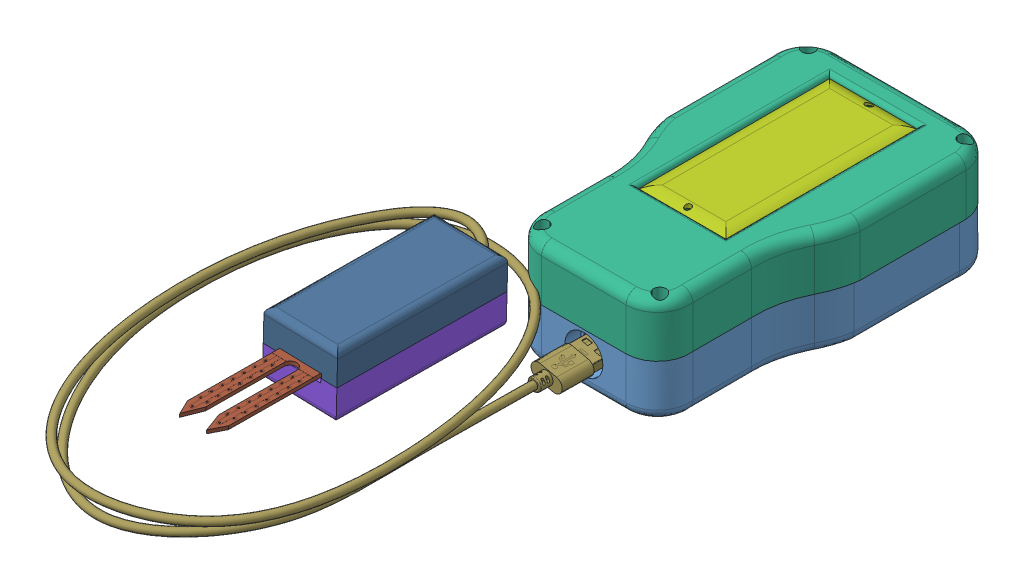
SolidWorks assembly Assem2, configuration Default. Lengths in mm.
Overall size (141.14 65.79 345.88).
13 component instances, 13 part files, 23 mates.
Components (placement in the parent):
- top-1: top [Default] at (67.1449 58.7615 115.5242) size (90.51 25.28 150)
- LCD-1: LCD [Default] at (67.061 64.7615 73.0708) x (-1 0 -0.000027) z (-0.000027 0 1) size (80.07 12.25 36.01)
- 1x4-keypad.stp-1: 1x4-keypad.stp [Default] at (67.0223 58.7615 110.1642) x (-1 0 0) z (0 0 1) size (69 7.1 20)
- WP1513GT.stp-1: WP1513GT.stp [Default] at (82.9683 65.6804 146.2483) x (0.92428 0 0.381715) z (0 -1 0) size (5.45 5.9 35.6)
- WP1513IT.stp-1: WP1513IT.stp [Default] at (51.3214 65.5043 146.2483) x (-0.785055 0 0.619426) z (0 -1 0) size (5.45 5.9 35.6)
- bottum-1: bottum [Default] at (67.1449 108.7615 115.5242) x (-1 0 0) z (0 0 1) size (90.51 25.68 150)
- BatteryLid-1: BatteryLid [Default] at (66.5924 106.7615 97.0343) x (1 0 0) z (0 1 0) size (42 91 2)
- sensortop-1: sensortop [Default] at (40.5905 82.4081 239.8119) x (-0.00509 0.003088 0.999982) z (-0.999709 0.023576 -0.005161) size (85 15 35)
- DHT11-1: DHT11 [Default] at (23.5549 91.3797 242.5446) x (0.999709 -0.023576 0.005161) z (-0.023591 -0.999717 0.002967) size (14 35.05 6.5)
- sensorbottum-1: sensorbottum [Default] at (17.8788 112.9519 239.602) x (-0.00509 0.003088 0.999982) z (0.999709 -0.023576 0.005161) size (85 15 35)
- Soil-Moisture-Sensor-Probe.stp-1: Soil-Moisture-Sensor-Probe.stp [Default] at (29.0609 98.1403 275.4531) x (0.999709 -0.023576 0.005161) z (0.00509 -0.003088 -0.999982) size (19.5 7 64.88)
- Тело9-1: Тело9 [По умолчанию] at (26.7121 97.0127 313.1556) x (0.004423 -0.007372 -0.999963) z (0.976916 -0.213544 0.005896) size (205.75 32.05 104.13)
- RockerSwitch-1: RockerSwitch [Default] at (32.3085 94.0875 80.8333) x (0 0 1) z (-1 0 0) size (21 14.8 24.8)
Mates (geometry in assembly coordinates):
- Parallel3: parallel anti-aligned: plane of top-1 through (96.4561 61.7615 87.4448) normal (0 1 0); plane of LCD-1 through (67.061 64.7615 73.0708) normal (0 -1 0)
- Coincident9: coincident anti-aligned: plane of top-1 through (62.7688 58.7615 97.6198) normal (0 -1 0); plane of 1x4-keypad.stp-1 through (67.0223 58.7615 110.1642) normal (0 1 0)
- Parallel6: parallel anti-aligned: line of top-1 through (28.1449 58.7615 88.9162) axis (1 0 0); line of 1x4-keypad.stp-1 through (101.5223 58.2615 120.1642) axis (-1 0 0)
- Concentric1: concentric aligned: cylinder of top-1 through (82.9683 68.7615 146.2483) axis (0 -1 0) radius 2.5; cone of WP1513GT.stp-1 through (82.9683 62.0304 146.2483) axis (0 -1 0)
- Concentric2: concentric aligned: cylinder of top-1 through (51.3214 68.7615 146.2483) axis (0 -1 0) radius 2.5; cone of WP1513IT.stp-1 through (51.3214 61.8543 146.2483) axis (0 -1 0)
- Parallel9: parallel anti-aligned: line of top-1 through (24.4204 83.7615 53.386) axis (-0.000027 0 1); line of LCD-1 through (27.0606 66.3615 88.5697) axis (0.000027 0 -1)
- Coincident18: coincident anti-aligned: plane of top-1 through (96.4561 61.7615 87.4448) normal (0 1 0); plane of LCD-1 through (67.061 61.7615 73.0708) normal (0 -1 0)
- Coincident21: coincident anti-aligned: line of top-1 through (37.1453 83.7615 39.2483) axis (1 0 0); line of bottum-1 through (97.1444 83.7615 39.2483) axis (-1 0 0)
- Coincident22: coincident anti-aligned: line of top-1 through (47.1449 83.7615 189.2483) axis (1 0 0); line of bottum-1 through (87.1449 83.7615 189.2483) axis (-1 0 0)
- Coincident25: coincident: cylinder of bottum-1 through (43.5924 106.7615 142.5343) axis (0 0 -1) radius 2; line of BatteryLid-1 through (45.5924 106.7615 51.5343) axis (0 0 1)
- Coincident26: coincident aligned: plane of bottum-1 through (71.5209 108.7615 97.6198) normal (0 1 0); plane of BatteryLid-1 through (66.5924 108.7615 97.0343) normal (0 1 0)
- Coincident27: coincident aligned: line of bottum-1 through (72.4595 106.7615 142.5343) axis (1 0 0); line of BatteryLid-1 through (45.5924 106.7615 142.5343) axis (1 0 0)
- Distance5: distance = 5.5591 mm anti-aligned: plane of sensortop-1 through (40.6612 85.4072 239.803) normal (0.023591 0.999717 -0.002967); plane of DHT11-1 through (23.5549 91.3797 242.5446) normal (-0.023591 -0.999717 0.002967)
- Parallel13: parallel aligned: line of sensortop-1 through (13.586 85.9699 214.1275) axis (-0.00509 0.003088 0.999982); line of DHT11-1 through (22.6478 92.3611 228.9867) axis (-0.00509 0.003088 0.999982)
- Coincident31: coincident anti-aligned: plane of sensorbottum-1 through (39.238 99.5499 275.2172) normal (-0.023591 -0.999717 0.002967); plane of Soil-Moisture-Sensor-Probe.stp-1 through (29.0666 99.81 281.9724) normal (0.023591 0.999717 -0.002967)
- Concentric3: concentric aligned: circle of sensorbottum-1; circle of Soil-Moisture-Sensor-Probe.stp-1
- Concentric4: concentric aligned: circle of sensorbottum-1; circle of Soil-Moisture-Sensor-Probe.stp-1
- Concentric5: concentric anti-aligned: circle of sensortop-1; circle of DHT11-1
- Coincident32: coincident anti-aligned: line of sensortop-1 through (25.4461 97.6668 205.1516) axis (-0.999709 0.023576 -0.005161); line of sensorbottum-1 through (11.9155 97.9859 205.0817) axis (0.999709 -0.023576 0.005161)
- Coincident33: coincident anti-aligned: line of sensortop-1 through (11.9155 97.9859 205.0817) axis (-0.00509 0.003088 0.999982); line of sensorbottum-1 through (11.5083 98.233 285.0803) axis (0.00509 -0.003088 -0.999982)
- Coincident34: coincident anti-aligned: plane of bottum-1 through (22.3085 83.7615 56.4595) normal (-1 0 0); plane of RockerSwitch-1 through (22.3085 94.0875 80.8333) normal (1 0 0)
- Parallel14: parallel anti-aligned: line of bottum-1 through (22.3085 103.7615 106.4595) axis (0 0 -1); line of RockerSwitch-1 through (21.8478 101.4875 70.3333) axis (0 0 1)
- Coincident36: coincident aligned: circle of top-1; circle of bottum-1
